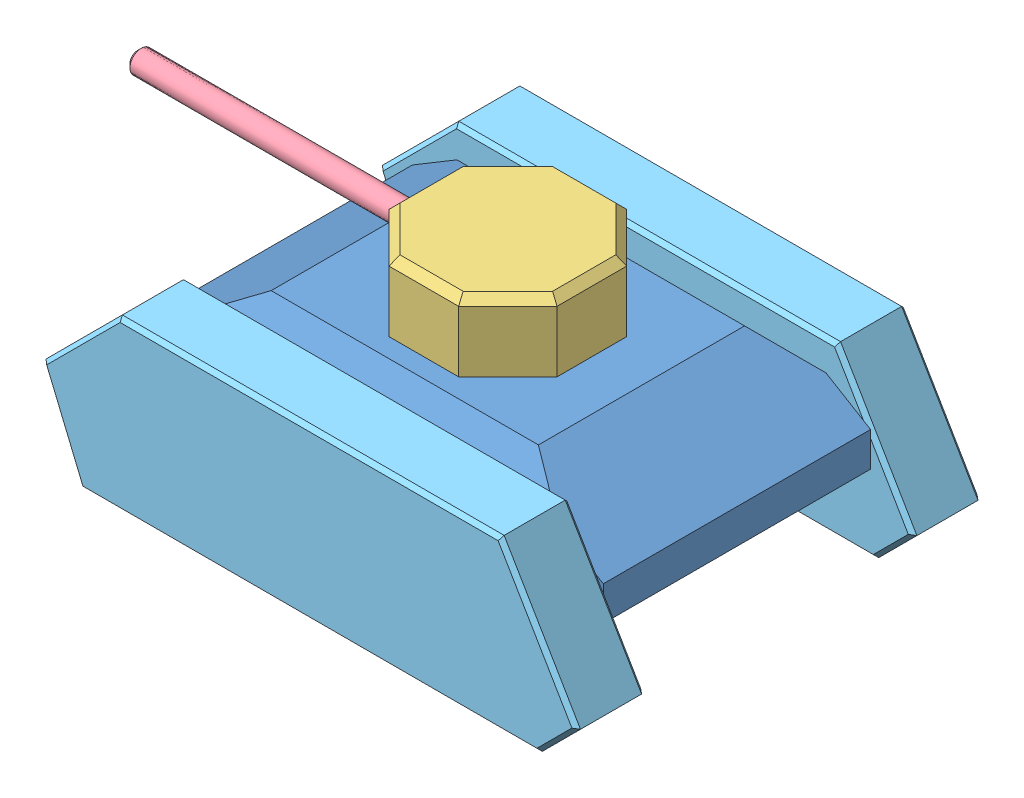
SolidWorks assembly Tank Assembly, configuration Default. Lengths in mm.
Overall size (168.14 62 106).
6 component instances, 5 part files, 10 mates.
Components (placement in the parent):
- Tank Body-1: Tank Body [Default] at (-11.118 0 5.8668) size (120 36 70)
- Dowel-1: Dowel [Default] at (-11.118 8 5.8668) size (9 20 9)
- Turret Post-1: Turret Post [Default] at (-11.118 18 5.8668) size (44 18 44)
- Tank Gun-1: Tank Gun [Default] at (-18.118 26 5.8668) x (-1 0 0) z (0 -0.388461 -0.921465) size (90 6 6)
- Tracks-1: Tracks [Default] at (-9.9736 -4 -38.1332) size (140 44 18)
- Tracks-2: Tracks [Default] at (-10.0897 -4 49.8668) size (140 44 18)
Mates (geometry in assembly coordinates):
- Coincident1: coincident anti-aligned: plane of Tank Body-1 through (-11.118 8 5.8668) normal (0 1 0); plane of Dowel-1 through (-11.118 8 5.8668) normal (0 -1 0)
- Coincident2: coincident aligned: circle of Tank Body-1; circle of Dowel-1
- Coincident3: coincident anti-aligned: plane of Tank Body-1 through (-71.118 18 -29.1332) normal (0 1 0); plane of Turret Post-1 through (-11.118 18 36.9795) normal (0 -1 0)
- Concentric1: concentric aligned: cylinder of Dowel-1 through (-11.118 28 5.8668) axis (0 -1 0) radius 4.5; cylinder of Turret Post-1 through (-11.118 27 5.8668) axis (0 -1 0) radius 4.5
- Coincident7: coincident anti-aligned: plane of Turret Post-1 through (-18.118 26 5.8668) normal (-1 0 0); plane of Tank Gun-1 through (-18.118 26 5.8668) normal (1 0 0)
- Coincident8: coincident aligned: circle of Turret Post-1; circle of Tank Gun-1
- Coincident15: coincident: plane of Tank Body-1 through (-71.118 18 -29.1332) normal (0 1 0); plane of Tracks-1 through (40.0264 18 -29.1332) normal (0 1 0)
- Coincident16: coincident anti-aligned: plane of Tank Body-1 through (48.882 18 -29.1332) normal (0 0 -1); plane of Tracks-1 through (-88.3069 18 -29.1332) normal (0 0 1)
- Coincident17: coincident: plane of Tank Body-1 through (48.882 18 40.8668) normal (0 0 1); plane of Tracks-2 through (-88.423 18 40.8668) normal (0 0 -1)
- Coincident18: coincident aligned: plane of Tank Body-1 through (-71.118 18 -29.1332) normal (0 1 0); plane of Tracks-2 through (39.9103 18 58.8668) normal (0 1 0)
